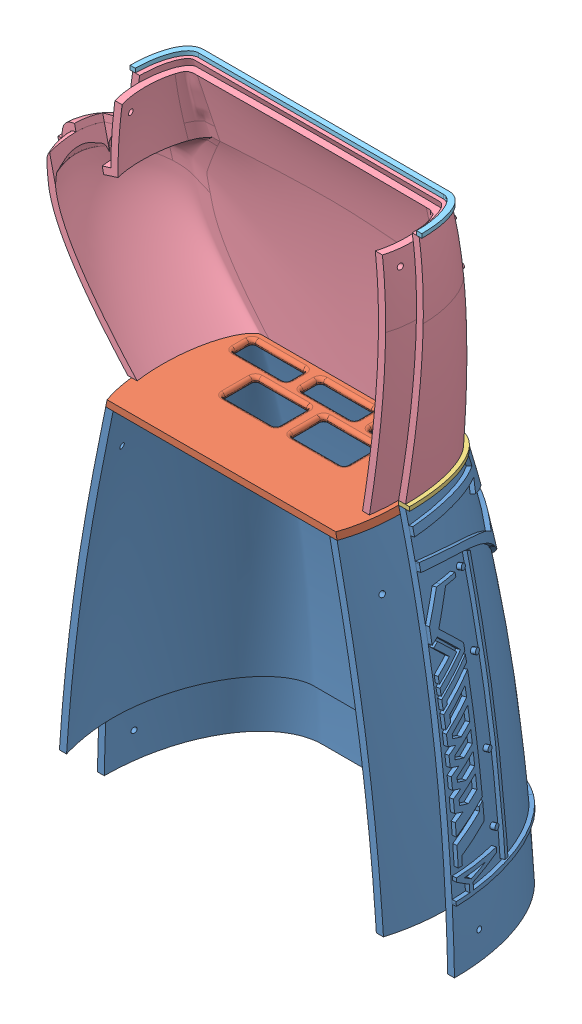
SolidWorks assembly Front Assembly, configuration Default. Lengths in mm.
Overall size (150.75 230.56 96.01).
5 component instances, 5 part files, 12 mates.
Components (placement in the parent):
- Arm Front-1: Arm Front [Default] at (26.9766 5.8272 128.3051) size (139.6 140.48 96.01)
- Arm Upper Lid-1: Arm Upper Lid [Default] at (26.9766 5.8272 128.3051) size (97.03 2.56 56.64)
- Hand Bottom Decoration Front-1: Hand Bottom Decoration Front [Default] at (26.9766 145.8272 128.3051) size (104.1 1.5 40.1)
- Hand Front-1: Hand Front [Default] at (26.9766 147.3272 128.3051) x (-1 0 0) z (0 0 -1) size (139.35 90.89 52.36)
- Hand Top Decoration-1: Hand Top Decoration [Default] at (26.9766 234.8272 128.3051) size (110.31 1.5 21.89)
Mates (geometry in assembly coordinates):
- Coincident1: coincident anti-aligned: plane of Arm Front-1 through (-38.0016 143.3272 186.1198) normal (0 1 0); plane of Arm Upper Lid-1 through (-36.0831 143.3272 200.785) normal (0 -1 0)
- Coincident4: coincident anti-aligned: plane of Arm Front-1 through (-6.0234 145.8272 128.3051) normal (0 1 0); plane of Hand Bottom Decoration Front-1 through (-6.0234 145.8272 128.3051) normal (0 -1 0)
- Coincident5: coincident: point of Arm Front-1; point of Hand Bottom Decoration Front-1
- Coincident6: coincident aligned: line of Arm Front-1 through (-6.0234 145.8272 158.3051) axis (1 0 0); line of Hand Bottom Decoration Front-1 through (-6.0234 145.8272 158.3051) axis (1 0 0)
- Coincident10: coincident aligned: plane of Arm Front-1 through (-42.8304 145.8391 128.3051) normal (0 0 1); plane of Hand Front-1 through (-55.0687 234.8391 128.3051) normal (0 0 1)
- Coincident11: coincident: point of Hand Bottom Decoration Front-1; point of Hand Front-1
- Coincident12: coincident anti-aligned: plane of Hand Bottom Decoration Front-1 through (-6.0234 147.3272 128.3051) normal (0 1 0); plane of Hand Front-1 through (59.9766 147.3272 128.3051) normal (0 -1 0)
- Coincident13: coincident anti-aligned: plane of Hand Front-1 through (71.9766 234.8272 128.3051) normal (0 1 0); plane of Hand Top Decoration-1 through (-18.0234 234.8272 128.3051) normal (0 -1 0)
- Coincident14: coincident: point of Hand Front-1; point of Hand Top Decoration-1
- Coincident15: coincident anti-aligned: line of Hand Front-1 through (71.9766 234.8272 143.3051) axis (-1 0 0); line of Hand Top Decoration-1 through (-18.0234 234.8272 143.3051) axis (1 0 0)
- Coincident16: coincident aligned: plane of Arm Front-1 through (102.9235 145.8391 148.3051) normal (0 0 1); plane of Arm Upper Lid-1 through (99.9673 145.8391 148.3051) normal (0 0 1)
- Coincident17: coincident: point of Arm Front-1; point of Arm Upper Lid-1
